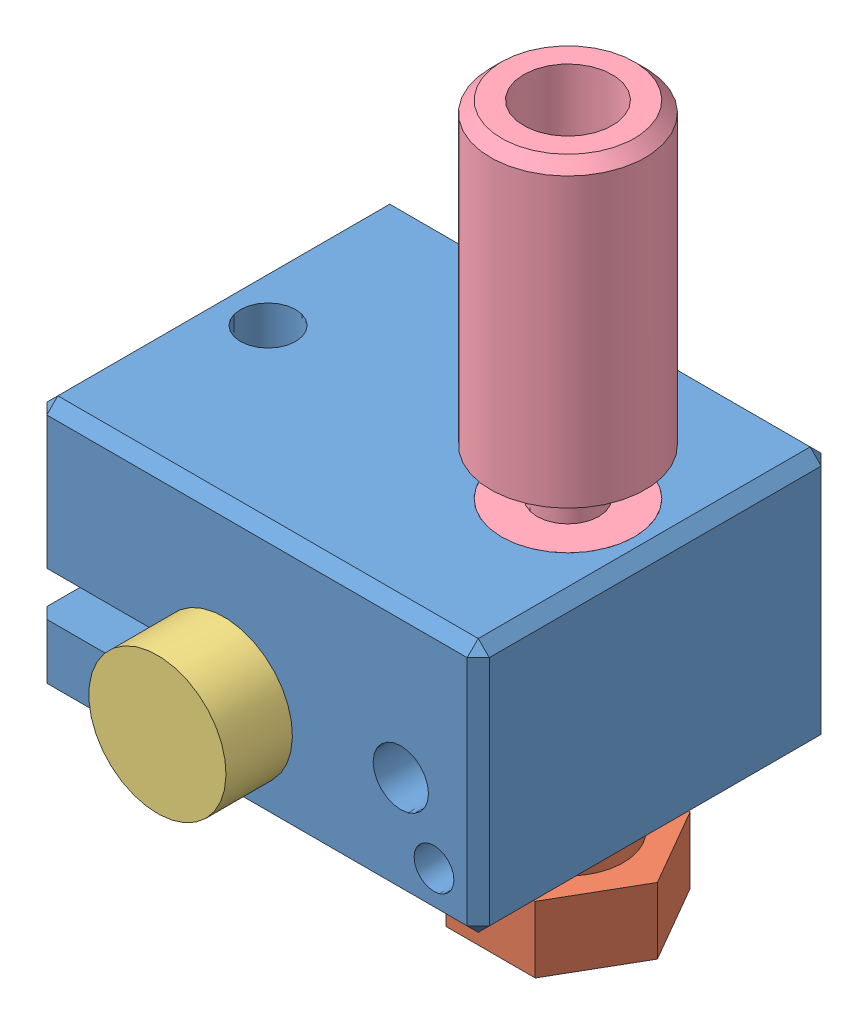
SolidWorks assembly Chimera_Chimera_Heater_Block, configuration Default. Lengths in mm.
Overall size (20.1 33.6 22).
4 component instances, 4 part files, 6 mates.
Components (placement in the parent):
- Chimera_v6_Heat_Block-1: Chimera_v6_Heat_Block [Default] at origin size (20 11.5 16)
- Chimera_v6_Nozzle-1: Chimera_v6_Nozzle [.4] at (6.0538 -6 0) size (8.08 12.5 7)
- Chimera_cartridge_heater-1: Chimera_cartridge_heater [Default] at (-1.5 -1.75 0) x (0 0 -1) z (0.39725 -0.91771 0) size (32 6.2 6.2)
- Chimera_Cyclops_Heat_Break-1: Chimera_Cyclops_Heat_Break [Default] at (6.0538 10.8 0) x (0 0 -1) z (1 0 0) size (7 21.1 7)
Mates (geometry in assembly coordinates):
- Concentric3: concentric anti-aligned: cylinder of Chimera_v6_Heat_Block-1 through (6.0538 5.75 0) axis (0 1 0) radius 3; cylinder of Chimera_v6_Nozzle-1 through (6.0538 -12.25 0) axis (0 -1 0) radius 3
- Concentric14: concentric anti-aligned: cylinder of Chimera_v6_Heat_Block-1 through (-1.5 -1.75 8) axis (0 0 -1) radius 3.05; cylinder of Chimera_cartridge_heater-1 through (-1.5 -1.75 11) axis (0 0 1) radius 3.1
- Width2: width anti-aligned: plane of Chimera_cartridge_heater-1 through (-2.5329 0.636 -11) normal (0 0 -1); plane of Chimera_v6_Heat_Block-1 through (-2.7315 1.0949 11) normal (0 0 1); plane of Chimera_cartridge_heater-1 through (-1.5 -1.75 8) normal (0 0 1); plane of Chimera_v6_Heat_Block-1 through (-1.5 -1.75 -8) normal (0 0 -1)
- Concentric1: concentric anti-aligned: cylinder of Chimera_Cyclops_Heat_Break-1 through (6.0538 0.25 0) axis (0 -1 0) radius 3; cylinder of Chimera_v6_Heat_Block-1 through (6.0538 5.75 0) axis (0 1 0) radius 3
- Coincident1: coincident aligned: plane of Chimera_Cyclops_Heat_Break-1 through (6.0538 5.75 -3) normal (0 1 0); plane of Chimera_v6_Heat_Block-1 through (-10 5.75 8) normal (0 1 0)
- Coincident6: coincident anti-aligned: plane of Chimera_Cyclops_Heat_Break-1 through (6.0538 0.25 -1) normal (0 -1 0); plane of Chimera_v6_Nozzle-1 through (7.4039 0.25 0) normal (0 1 0)
